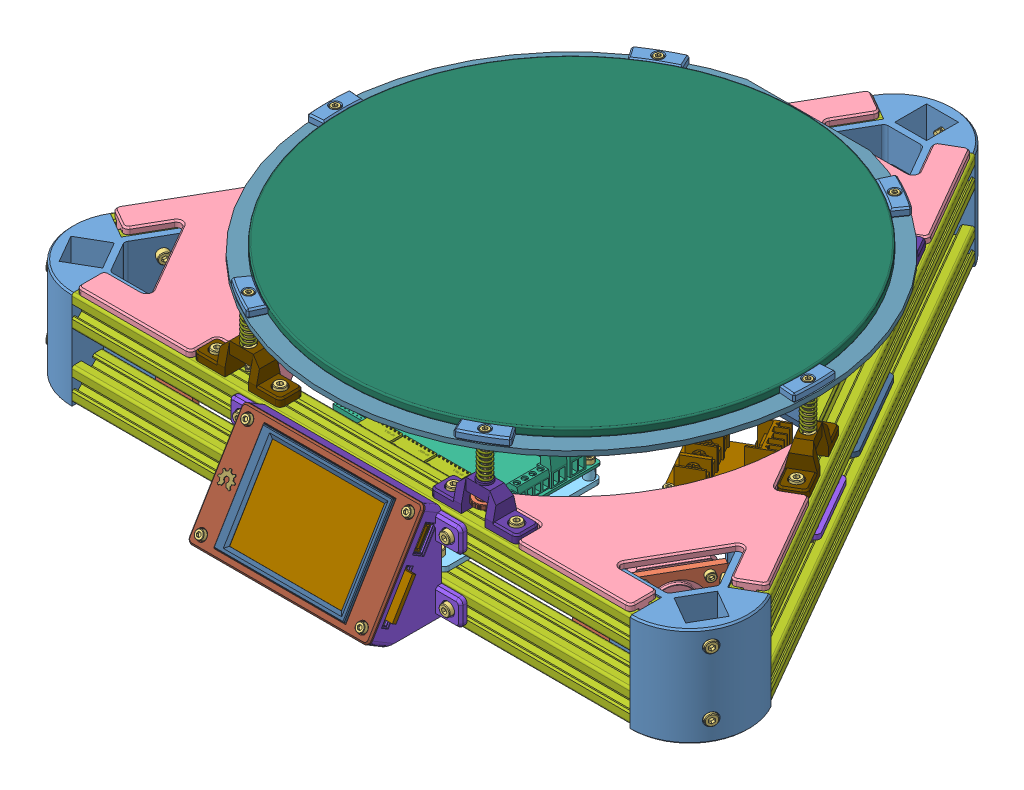
SolidWorks assembly Base Assembly, configuration Default. Lengths in mm.
Overall size (443.23 111.95 443.3).
179 component instances, 29 part files, 111 mates.
Components (placement in the parent):
- Drive Assembly-1: Drive Assembly [Default] at origin size (114.53 65.1 95.5)
  - Bottom Corner Support-1: Bottom Corner Support [Default] at origin size (78.83 63 82.18)
  - Stepper Mount-1: Stepper Mount [Default] at (0 0 0) x (1 0 0) z (0 0 1) size (55.32 60 75.5)
  - socket head cap screw_am-1: socket head cap screw_am [B18.3.1M - 3 x 0.5 x 20 Hex SHCS -- 20SHX] at (53.2197 60 -64.6791) x (0 -1 0) z (-0.546944 0 0.837169) size (23 5.5 5.5)
  - socket head cap screw_am-2: socket head cap screw_am [B18.3.1M - 3 x 0.5 x 20 Hex SHCS -- 20SHX] at (53.2197 0 -64.6791) x (0 1 0) z (-0.546944 0 0.837169) size (23 5.5 5.5)
  - socket head cap screw_am-3: socket head cap screw_am [B18.3.1M - 3 x 0.5 x 20 Hex SHCS -- 20SHX] at (82.6236 60 -13.75) x (0 -1 0) z (-0.546944 0 0.837169) size (23 5.5 5.5)
  - socket head cap screw_am-4: socket head cap screw_am [B18.3.1M - 3 x 0.5 x 20 Hex SHCS -- 20SHX] at (82.6236 0 -13.75) x (0 1 0) z (-0.546944 0 0.837169) size (23 5.5 5.5)
  - socket head cap screw_am-5: socket head cap screw_am [B18.3.1M - 4 x 0.7 x 8 Hex SHCS -- 8SHX] at (63.9931 10 -74.8395) x (-0.866026 0 -0.5) z (0.09665 0.98114 -0.167402) size (12 7 7)
  - socket head cap screw_am-6: socket head cap screw_am [B18.3.1M - 4 x 0.7 x 8 Hex SHCS -- 8SHX] at (48.7135 50 -48.3742) x (-0.866025 0 -0.5) z (-0.190925 0.924225 0.330691) size (12 7 7)
  - socket head cap screw_am-7: socket head cap screw_am [B18.3.1M - 4 x 0.7 x 8 Hex SHCS -- 8SHX] at (48.7135 10 -48.3742) x (-0.866025 0 -0.5) z (-0.190925 0.924225 0.330691) size (12 7 7)
  - socket head cap screw_am-8: socket head cap screw_am [B18.3.1M - 4 x 0.7 x 8 Hex SHCS -- 8SHX] at (66.25 10 -18) x (0 0 1) z (-1 0 0) size (12 7 7)
  - socket head cap screw_am-9: socket head cap screw_am [B18.3.1M - 4 x 0.7 x 8 Hex SHCS -- 8SHX] at (63.9931 50 -74.8395) x (-0.866026 0 -0.5) z (-0.190925 0.924225 0.330691) size (12 7 7)
  - socket head cap screw_am-10: socket head cap screw_am [B18.3.1M - 4 x 0.7 x 8 Hex SHCS -- 8SHX] at (66.25 50 -18) x (0 0 1) z (-1 0 0) size (12 7 7)
  - socket head cap screw_am-11: socket head cap screw_am [B18.3.1M - 4 x 0.7 x 8 Hex SHCS -- 8SHX] at (96.8094 10 -18.0001) x (0 0 1) z (-1 0 0) size (12 7 7)
  - socket head cap screw_am-12: socket head cap screw_am [B18.3.1M - 4 x 0.7 x 8 Hex SHCS -- 8SHX] at (96.8094 50 -18.0001) x (0 0 1) z (-1 0 0) size (12 7 7)
  - socket head cap screw_am-13: socket head cap screw_am [B18.3.1M - 4 x 0.7 x 8 Hex SHCS -- 8SHX] at (14.3627 50 -8.2923) x (0.866025 0 -0.5) z (-0.499976 0.009715 -0.865985) size (12 7 7)
  - socket head cap screw_am-14: socket head cap screw_am [B18.3.1M - 4 x 0.7 x 8 Hex SHCS -- 8SHX] at (14.3627 10 -8.2923) x (0.866025 0 -0.5) z (0.5 0 0.866025) size (12 7 7)
  - socket head cap screw_am-15: socket head cap screw_am [B18.3.1M - 3 x 0.5 x 8 Hex SHCS -- 8SHX] at (57.357 45.5 -51.013) x (0.866025 0 -0.5) z (0.5 0 0.866025) size (11 5.5 5.5)
  - socket head cap screw_am-16: socket head cap screw_am [B18.3.1M - 3 x 0.5 x 8 Hex SHCS -- 8SHX] at (72.857 45.5 -24.1662) x (0.866025 0 -0.5) z (0.5 0 0.866025) size (11 5.5 5.5)
  - socket head cap screw_am-17: socket head cap screw_am [B18.3.1M - 3 x 0.5 x 8 Hex SHCS -- 8SHX] at (57.357 14.5 -51.013) x (0.866025 0 -0.5) z (0.5 0 0.866025) size (11 5.5 5.5)
  - socket head cap screw_am-18: socket head cap screw_am [B18.3.1M - 3 x 0.5 x 8 Hex SHCS -- 8SHX] at (72.857 14.5 -24.1662) x (0.866025 0 -0.5) z (0.5 0 0.866025) size (11 5.5 5.5)
  - Drive Stepper-1: Drive Stepper [Défaut] at (69.4371 30 -40.0896) x (-0.5 0 -0.866025) z (0.866025 0 -0.5) size (45.3 42.3 72)
  - Drive Pulley-1: Drive Pulley [Конфигурация1] at (64.241 30 -37.0896) x (-0.866025 0 0.5) z (-0.435421 -0.491563 -0.754171) size (16 16 16)
  - Rubber Foot-1: Rubber Foot [Default] at (28.7942 -2.5 -16.6244) x (1 0 0) z (0 0 -1) size (15.2 2.6 15.2)
- Horizontal Extrusion-1: Horizontal Extrusion [Default] at (48 10 0) x (0 0 -1) z (1 0 0) size (20 20 354)
- Horizontal Extrusion-2: Horizontal Extrusion [Default] at (48 50 0) x (0 0 -1) z (1 0 0) size (20 20 354)
- Horizontal Extrusion-3: Horizontal Extrusion [Default] at (24 50 -41.5692) x (-0.866025 0 -0.5) z (0.5 0 -0.866025) size (20 20 354)
- Horizontal Extrusion-4: Horizontal Extrusion [Default] at (24 10 -41.5692) x (-0.866025 0 -0.5) z (0.5 0 -0.866025) size (20 20 354)
- Drive Assembly-2: Drive Assembly [Default] at (450 0 0) x (-0.5 0 -0.866025) z (0.866025 0 -0.5) size (114.53 65.1 95.5)
  - Bottom Corner Support-1: Bottom Corner Support [Default] at origin size (78.83 63 82.18)
  - Stepper Mount-1: Stepper Mount [Default] at (0 0 0) x (1 0 0) z (0 0 1) size (55.32 60 75.5)
  - socket head cap screw_am-1: socket head cap screw_am [B18.3.1M - 3 x 0.5 x 20 Hex SHCS -- 20SHX] at (53.2197 60 -64.6791) x (0 -1 0) z (-0.546944 0 0.837169) size (23 5.5 5.5)
  - socket head cap screw_am-2: socket head cap screw_am [B18.3.1M - 3 x 0.5 x 20 Hex SHCS -- 20SHX] at (53.2197 0 -64.6791) x (0 1 0) z (-0.546944 0 0.837169) size (23 5.5 5.5)
  - socket head cap screw_am-3: socket head cap screw_am [B18.3.1M - 3 x 0.5 x 20 Hex SHCS -- 20SHX] at (82.6236 60 -13.75) x (0 -1 0) z (-0.546944 0 0.837169) size (23 5.5 5.5)
  - socket head cap screw_am-4: socket head cap screw_am [B18.3.1M - 3 x 0.5 x 20 Hex SHCS -- 20SHX] at (82.6236 0 -13.75) x (0 1 0) z (-0.546944 0 0.837169) size (23 5.5 5.5)
  - socket head cap screw_am-5: socket head cap screw_am [B18.3.1M - 4 x 0.7 x 8 Hex SHCS -- 8SHX] at (63.9931 10 -74.8395) x (-0.866026 0 -0.5) z (0.09665 0.98114 -0.167402) size (12 7 7)
  - socket head cap screw_am-6: socket head cap screw_am [B18.3.1M - 4 x 0.7 x 8 Hex SHCS -- 8SHX] at (48.7135 50 -48.3742) x (-0.866025 0 -0.5) z (-0.190925 0.924225 0.330691) size (12 7 7)
  - socket head cap screw_am-7: socket head cap screw_am [B18.3.1M - 4 x 0.7 x 8 Hex SHCS -- 8SHX] at (48.7135 10 -48.3742) x (-0.866025 0 -0.5) z (-0.190925 0.924225 0.330691) size (12 7 7)
  - socket head cap screw_am-8: socket head cap screw_am [B18.3.1M - 4 x 0.7 x 8 Hex SHCS -- 8SHX] at (66.25 10 -18) x (0 0 1) z (-1 0 0) size (12 7 7)
  - socket head cap screw_am-9: socket head cap screw_am [B18.3.1M - 4 x 0.7 x 8 Hex SHCS -- 8SHX] at (63.9931 50 -74.8395) x (-0.866026 0 -0.5) z (-0.190925 0.924225 0.330691) size (12 7 7)
  - socket head cap screw_am-10: socket head cap screw_am [B18.3.1M - 4 x 0.7 x 8 Hex SHCS -- 8SHX] at (66.25 50 -18) x (0 0 1) z (-1 0 0) size (12 7 7)
  - socket head cap screw_am-11: socket head cap screw_am [B18.3.1M - 4 x 0.7 x 8 Hex SHCS -- 8SHX] at (96.8094 10 -18.0001) x (0 0 1) z (-1 0 0) size (12 7 7)
  - socket head cap screw_am-12: socket head cap screw_am [B18.3.1M - 4 x 0.7 x 8 Hex SHCS -- 8SHX] at (96.8094 50 -18.0001) x (0 0 1) z (-1 0 0) size (12 7 7)
  - socket head cap screw_am-13: socket head cap screw_am [B18.3.1M - 4 x 0.7 x 8 Hex SHCS -- 8SHX] at (14.3627 50 -8.2923) x (0.866025 0 -0.5) z (-0.499976 0.009715 -0.865985) size (12 7 7)
  - socket head cap screw_am-14: socket head cap screw_am [B18.3.1M - 4 x 0.7 x 8 Hex SHCS -- 8SHX] at (14.3627 10 -8.2923) x (0.866025 0 -0.5) z (0.5 0 0.866025) size (12 7 7)
  - socket head cap screw_am-15: socket head cap screw_am [B18.3.1M - 3 x 0.5 x 8 Hex SHCS -- 8SHX] at (57.357 45.5 -51.013) x (0.866025 0 -0.5) z (0.5 0 0.866025) size (11 5.5 5.5)
  - socket head cap screw_am-16: socket head cap screw_am [B18.3.1M - 3 x 0.5 x 8 Hex SHCS -- 8SHX] at (72.857 45.5 -24.1662) x (0.866025 0 -0.5) z (0.5 0 0.866025) size (11 5.5 5.5)
  - socket head cap screw_am-17: socket head cap screw_am [B18.3.1M - 3 x 0.5 x 8 Hex SHCS -- 8SHX] at (57.357 14.5 -51.013) x (0.866025 0 -0.5) z (0.5 0 0.866025) size (11 5.5 5.5)
  - socket head cap screw_am-18: socket head cap screw_am [B18.3.1M - 3 x 0.5 x 8 Hex SHCS -- 8SHX] at (72.857 14.5 -24.1662) x (0.866025 0 -0.5) z (0.5 0 0.866025) size (11 5.5 5.5)
  - Drive Stepper-1: Drive Stepper [Défaut] at (69.4371 30 -40.0896) x (-0.5 0 -0.866025) z (0.866025 0 -0.5) size (45.3 42.3 72)
  - Drive Pulley-1: Drive Pulley [Конфигурация1] at (64.241 30 -37.0896) x (-0.866025 0 0.5) z (-0.435421 -0.491563 -0.754171) size (16 16 16)
  - Rubber Foot-1: Rubber Foot [Default] at (28.7942 -2.5 -16.6244) x (1 0 0) z (0 0 -1) size (15.2 2.6 15.2)
- Drive Assembly-3: Drive Assembly [Default] at (225 0 -389.7114) x (-0.5 0 0.866025) z (-0.866025 0 -0.5) size (114.53 65.1 95.5)
  - Bottom Corner Support-1: Bottom Corner Support [Default] at origin size (78.83 63 82.18)
  - Stepper Mount-1: Stepper Mount [Default] at (0 0 0) x (1 0 0) z (0 0 1) size (55.32 60 75.5)
  - socket head cap screw_am-1: socket head cap screw_am [B18.3.1M - 3 x 0.5 x 20 Hex SHCS -- 20SHX] at (53.2197 60 -64.6791) x (0 -1 0) z (-0.546944 0 0.837169) size (23 5.5 5.5)
  - socket head cap screw_am-2: socket head cap screw_am [B18.3.1M - 3 x 0.5 x 20 Hex SHCS -- 20SHX] at (53.2197 0 -64.6791) x (0 1 0) z (-0.546944 0 0.837169) size (23 5.5 5.5)
  - socket head cap screw_am-3: socket head cap screw_am [B18.3.1M - 3 x 0.5 x 20 Hex SHCS -- 20SHX] at (82.6236 60 -13.75) x (0 -1 0) z (-0.546944 0 0.837169) size (23 5.5 5.5)
  - socket head cap screw_am-4: socket head cap screw_am [B18.3.1M - 3 x 0.5 x 20 Hex SHCS -- 20SHX] at (82.6236 0 -13.75) x (0 1 0) z (-0.546944 0 0.837169) size (23 5.5 5.5)
  - socket head cap screw_am-5: socket head cap screw_am [B18.3.1M - 4 x 0.7 x 8 Hex SHCS -- 8SHX] at (63.9931 10 -74.8395) x (-0.866026 0 -0.5) z (0.09665 0.98114 -0.167402) size (12 7 7)
  - socket head cap screw_am-6: socket head cap screw_am [B18.3.1M - 4 x 0.7 x 8 Hex SHCS -- 8SHX] at (48.7135 50 -48.3742) x (-0.866025 0 -0.5) z (-0.190925 0.924225 0.330691) size (12 7 7)
  - socket head cap screw_am-7: socket head cap screw_am [B18.3.1M - 4 x 0.7 x 8 Hex SHCS -- 8SHX] at (48.7135 10 -48.3742) x (-0.866025 0 -0.5) z (-0.190925 0.924225 0.330691) size (12 7 7)
  - socket head cap screw_am-8: socket head cap screw_am [B18.3.1M - 4 x 0.7 x 8 Hex SHCS -- 8SHX] at (66.25 10 -18) x (0 0 1) z (-1 0 0) size (12 7 7)
  - socket head cap screw_am-9: socket head cap screw_am [B18.3.1M - 4 x 0.7 x 8 Hex SHCS -- 8SHX] at (63.9931 50 -74.8395) x (-0.866026 0 -0.5) z (-0.190925 0.924225 0.330691) size (12 7 7)
  - socket head cap screw_am-10: socket head cap screw_am [B18.3.1M - 4 x 0.7 x 8 Hex SHCS -- 8SHX] at (66.25 50 -18) x (0 0 1) z (-1 0 0) size (12 7 7)
  - socket head cap screw_am-11: socket head cap screw_am [B18.3.1M - 4 x 0.7 x 8 Hex SHCS -- 8SHX] at (96.8094 10 -18.0001) x (0 0 1) z (-1 0 0) size (12 7 7)
  - socket head cap screw_am-12: socket head cap screw_am [B18.3.1M - 4 x 0.7 x 8 Hex SHCS -- 8SHX] at (96.8094 50 -18.0001) x (0 0 1) z (-1 0 0) size (12 7 7)
  - socket head cap screw_am-13: socket head cap screw_am [B18.3.1M - 4 x 0.7 x 8 Hex SHCS -- 8SHX] at (14.3627 50 -8.2923) x (0.866025 0 -0.5) z (-0.499976 0.009715 -0.865985) size (12 7 7)
  - socket head cap screw_am-14: socket head cap screw_am [B18.3.1M - 4 x 0.7 x 8 Hex SHCS -- 8SHX] at (14.3627 10 -8.2923) x (0.866025 0 -0.5) z (0.5 0 0.866025) size (12 7 7)
  - socket head cap screw_am-15: socket head cap screw_am [B18.3.1M - 3 x 0.5 x 8 Hex SHCS -- 8SHX] at (57.357 45.5 -51.013) x (0.866025 0 -0.5) z (0.5 0 0.866025) size (11 5.5 5.5)
  - socket head cap screw_am-16: socket head cap screw_am [B18.3.1M - 3 x 0.5 x 8 Hex SHCS -- 8SHX] at (72.857 45.5 -24.1662) x (0.866025 0 -0.5) z (0.5 0 0.866025) size (11 5.5 5.5)
  - socket head cap screw_am-17: socket head cap screw_am [B18.3.1M - 3 x 0.5 x 8 Hex SHCS -- 8SHX] at (57.357 14.5 -51.013) x (0.866025 0 -0.5) z (0.5 0 0.866025) size (11 5.5 5.5)
  - socket head cap screw_am-18: socket head cap screw_am [B18.3.1M - 3 x 0.5 x 8 Hex SHCS -- 8SHX] at (72.857 14.5 -24.1662) x (0.866025 0 -0.5) z (0.5 0 0.866025) size (11 5.5 5.5)
  - Drive Stepper-1: Drive Stepper [Défaut] at (69.4371 30 -40.0896) x (-0.5 0 -0.866025) z (0.866025 0 -0.5) size (45.3 42.3 72)
  - Drive Pulley-1: Drive Pulley [Конфигурация1] at (64.241 30 -37.0896) x (-0.866025 0 0.5) z (-0.435421 -0.491563 -0.754171) size (16 16 16)
  - Rubber Foot-1: Rubber Foot [Default] at (28.7942 -2.5 -16.6244) x (1 0 0) z (0 0 -1) size (15.2 2.6 15.2)
- Horizontal Extrusion-5: Horizontal Extrusion [Default] at (249 50 -348.1422) x (0.866025 0 -0.5) z (0.5 0 0.866025) size (20 20 354)
- Horizontal Extrusion-6: Horizontal Extrusion [Default] at (249 10 -348.1422) x (0.866025 0 -0.5) z (0.5 0 0.866025) size (20 20 354)
- Touchscreen Assembly-1: Touchscreen Assembly [Default] at (167.5 0 10) size (147 66.7 53)
  - Touchscreen Housing-1: Touchscreen Housing [Default] at origin size (147 65.67 45.48)
  - Touchscreen-1: Touchscreen [Default] at (57.5 33.7343 24.242) x (1 0 0) z (0 -0.857143 0.515079) size (116.5 15.5 65)
  - Touchscreen Bezel-1: Touchscreen Bezel [Default] at (15.2 8.5802 43.7328) x (1 0 0) z (0 -0.857143 0.515079) size (84.6 3.5 63.2)
  - Touchscreen Face-1: Touchscreen Face [Default] at (0 5.6659 45.4841) x (1 0 0) z (0 -0.857143 0.515079) size (115 2 70)
  - Logo-1: Logo [Default] at (8.2907 22.4701 36.786) x (-1 0 0) z (0 0.857143 -0.515079) size (10.55 1.3 9.36)
  - socket head cap screw_am-1: socket head cap screw_am [B18.3.1M - 3 x 0.5 x 8 Hex SHCS -- 8SHX] at (6.5 62.1548 16.2052) x (0 -0.515079 -0.857143) z (0.869565 -0.423273 0.254355) size (11 5.5 5.5)
  - socket head cap screw_am-2: socket head cap screw_am [B18.3.1M - 3 x 0.5 x 8 Hex SHCS -- 8SHX] at (108.5 62.1548 16.2052) x (0 -0.515079 -0.857143) z (0.869565 -0.423273 0.254355) size (11 5.5 5.5)
  - socket head cap screw_am-3: socket head cap screw_am [B18.3.1M - 3 x 0.5 x 8 Hex SHCS -- 8SHX] at (6.5 13.2976 45.5646) x (0 -0.515079 -0.857143) z (0.869565 -0.423273 0.254355) size (11 5.5 5.5)
  - socket head cap screw_am-4: socket head cap screw_am [B18.3.1M - 3 x 0.5 x 8 Hex SHCS -- 8SHX] at (108.5 13.2976 45.5646) x (0 -0.515079 -0.857143) z (0.869565 -0.423273 0.254355) size (11 5.5 5.5)
  - hex nut style 1_am-1: hex nut style 1_am [B18.2.4.1M - Hex nut, Style 1,  M3 x 0.5 --D-S] at (108.5 9.3057 38.9218) x (-1 0 0) z (0 0.515079 0.857143) size (5.5 6.35 2.4)
  - hex nut style 1_am-2: hex nut style 1_am [B18.2.4.1M - Hex nut, Style 1,  M3 x 0.5 --D-S] at (108.5 56.9267 7.5052) x (1 0 0) z (0 -0.515079 -0.857143) size (5.5 6.35 2.4)
  - hex nut style 1_am-3: hex nut style 1_am [B18.2.4.1M - Hex nut, Style 1,  M3 x 0.5 --D-S] at (6.5 8.0696 36.8646) x (1 0 0) z (0 -0.515079 -0.857143) size (5.5 6.35 2.4)
  - hex nut style 1_am-4: hex nut style 1_am [B18.2.4.1M - Hex nut, Style 1,  M3 x 0.5 --D-S] at (6.5 56.9267 7.5052) x (1 0 0) z (0 -0.515079 -0.857143) size (5.5 6.35 2.4)
  - socket head cap screw_am-6: socket head cap screw_am [B18.3.1M - 4 x 0.7 x 8 Hex SHCS -- 8SHX] at (-8 50 6.5) x (0 0 -1) z (0.869565 -0.493818 0) size (12 7 7)
  - socket head cap screw_am-7: socket head cap screw_am [B18.3.1M - 4 x 0.7 x 8 Hex SHCS -- 8SHX] at (-8 10 6.5) x (0 0 -1) z (0.923728 0.383049 0) size (12 7 7)
  - socket head cap screw_am-8: socket head cap screw_am [B18.3.1M - 4 x 0.7 x 8 Hex SHCS -- 8SHX] at (123 50 6.5) x (0 0 -1) z (0.923728 0.383049 0) size (12 7 7)
  - socket head cap screw_am-9: socket head cap screw_am [B18.3.1M - 4 x 0.7 x 8 Hex SHCS -- 8SHX] at (123 10 6.5) x (0 0 -1) z (0.923728 0.383049 0) size (12 7 7)
- Bed Assembly-1: Bed Assembly [Default] at (225 98.5 -129.9038) size (340.49 52.35 312.47)
  - Heat Bed-1: Heat Bed [Default] at origin size (310 3.1 305.01)
  - Print Surface-1: Print Surface [Default] at (0 3.1 0) size (290 5.25 290)
  - Bed Leveling Spring-1: Bed Leveling Spring [Default] at (150 -20 0) size (8.52 22.05 8.3)
  - Bed Leveling Spring-2: Bed Leveling Spring [Default] at (75 -20 129.9038) size (8.52 22.05 8.3)
  - Bed Leveling Spring-3: Bed Leveling Spring [Default] at (-75 -20 129.9038) size (8.52 22.05 8.3)
  - Bed Leveling Spring-4: Bed Leveling Spring [Default] at (-150 -20 0) size (8.52 22.05 8.3)
  - Bed Leveling Spring-5: Bed Leveling Spring [Default] at (-75 -20 -129.9038) size (8.52 22.05 8.3)
  - Bed Leveling Spring-6: Bed Leveling Spring [Default] at (75 -20 -129.9038) size (8.52 22.05 8.3)
  - Bed Foot-1: Bed Foot [Default] at (47.5 -38.5 122.4038) size (55 20.3 15)
  - Bed Static Foot-2: Bed Static Foot [Default] at (-102.5 -38.5 122.4038) size (55 18.5 15)
  - Bed Foot-3: Bed Foot [Default] at (82.2548 -38.5 -102.3381) x (-0.5 0 -0.866025) z (0.866025 0 -0.5) size (55 20.3 15)
  - Bed Static Foot-4: Bed Static Foot [Default] at (-95.2452 -38.5 -109.8381) x (0.5 0 -0.866025) z (0.866025 0 0.5) size (55 18.5 15)
  - Bed Foot-5: Bed Foot [Default] at (-170.2452 -38.5 20.0657) x (0.5 0 -0.866025) z (0.866025 0 0.5) size (55 20.3 15)
  - Bed Static Foot-6: Bed Static Foot [Default] at (157.2548 -38.5 27.5657) x (-0.5 0 -0.866025) z (0.866025 0 -0.5) size (55 18.5 15)
  - Print Surface Clip-1: Print Surface Clip [Default] at (0 3.1 0) x (0.866025 0 0.5) z (-0.5 0 0.866025) size (26.84 5.25 10.55)
  - Print Surface Clip-2: Print Surface Clip [Default] at (0 3.1 0) x (0.866025 0 -0.5) z (0.5 0 0.866025) size (26.84 5.25 10.55)
  - Print Surface Clip-3: Print Surface Clip [Default] at (0 3.1 0) x (0 0 -1) z (1 0 0) size (26.84 5.25 10.55)
  - Print Surface Clip-4: Print Surface Clip [Default] at (0 3.1 0) x (-0.866025 0 -0.5) z (0.5 0 -0.866025) size (26.84 5.25 10.55)
  - Print Surface Clip-5: Print Surface Clip [Default] at (0 3.1 0) x (-0.866025 0 0.5) z (-0.5 0 -0.866025) size (26.84 5.25 10.55)
  - Print Surface Clip-6: Print Surface Clip [Default] at (0 3.1 0) x (0 0 1) z (-1 0 0) size (26.84 5.25 10.55)
  - socket head cap screw_am-1: socket head cap screw_am [B18.3.1M - 3 x 0.5 x 40 Hex SHCS -- 40SHX] at (-150 8.35 0) x (0 -1 0) z (-0.546944 0 0.837169) size (43 5.5 5.5)
  - socket head cap screw_am-2: socket head cap screw_am [B18.3.1M - 3 x 0.5 x 40 Hex SHCS -- 40SHX] at (-75 8.35 129.9038) x (0 -1 0) z (-0.546944 0 0.837169) size (43 5.5 5.5)
  - socket head cap screw_am-3: socket head cap screw_am [B18.3.1M - 3 x 0.5 x 40 Hex SHCS -- 40SHX] at (75 8.35 129.9038) x (0 -1 0) z (-0.546944 0 0.837169) size (43 5.5 5.5)
  - socket head cap screw_am-4: socket head cap screw_am [B18.3.1M - 3 x 0.5 x 40 Hex SHCS -- 40SHX] at (150 8.35 0) x (0 -1 0) z (-0.546944 0 0.837169) size (43 5.5 5.5)
  - socket head cap screw_am-5: socket head cap screw_am [B18.3.1M - 3 x 0.5 x 40 Hex SHCS -- 40SHX] at (75 8.35 -129.9038) x (0 -1 0) z (-0.546944 0 0.837169) size (43 5.5 5.5)
  - socket head cap screw_am-6: socket head cap screw_am [B18.3.1M - 3 x 0.5 x 40 Hex SHCS -- 40SHX] at (-75 8.35 -129.9038) x (0 -1 0) z (-0.546944 0 0.837169) size (43 5.5 5.5)
  - Bed Leveling Knob-1: Bed Leveling Knob [Default] at (75 -32 129.9038) x (0 1 0) z (0 0 1) size (12 14 14)
  - Bed Leveling Knob-3: Bed Leveling Knob [Default] at (75 -32 -129.9038) x (0 1 0) z (0 0 1) size (12 14 14)
  - Bed Leveling Knob-5: Bed Leveling Knob [Default] at (-150 -32 0) x (0 1 0) z (0 0 1) size (12 14 14)
  - socket head cap screw_am-7: socket head cap screw_am [B18.3.1M - 4 x 0.7 x 8 Hex SHCS -- 8SHX] at (-65 -32 -147.2243) x (0 -1 0) z (0 0 1) size (12 7 7)
  - socket head cap screw_am-8: socket head cap screw_am [B18.3.1M - 4 x 0.7 x 8 Hex SHCS -- 8SHX] at (-85 -32 -112.5833) x (0 -1 0) z (-0.546944 0 0.837169) size (12 7 7)
  - socket head cap screw_am-9: socket head cap screw_am [B18.3.1M - 4 x 0.7 x 8 Hex SHCS -- 8SHX] at (-140 -32 -17.3205) x (0 -1 0) z (-0.546944 0 0.837169) size (12 7 7)
  - socket head cap screw_am-10: socket head cap screw_am [B18.3.1M - 4 x 0.7 x 8 Hex SHCS -- 8SHX] at (-160 -32 17.3205) x (0 -1 0) z (-0.546944 0 0.837169) size (12 7 7)
  - socket head cap screw_am-11: socket head cap screw_am [B18.3.1M - 4 x 0.7 x 8 Hex SHCS -- 8SHX] at (65 -32 -147.2243) x (0 -1 0) z (-0.546944 0 0.837169) size (12 7 7)
  - socket head cap screw_am-12: socket head cap screw_am [B18.3.1M - 4 x 0.7 x 8 Hex SHCS -- 8SHX] at (85 -32 -112.5833) x (0 -1 0) z (-0.546944 0 0.837169) size (12 7 7)
  - socket head cap screw_am-13: socket head cap screw_am [B18.3.1M - 4 x 0.7 x 8 Hex SHCS -- 8SHX] at (140 -32 -17.3205) x (0 -1 0) z (-0.546944 0 0.837169) size (12 7 7)
  - socket head cap screw_am-14: socket head cap screw_am [B18.3.1M - 4 x 0.7 x 8 Hex SHCS -- 8SHX] at (160 -32 17.3205) x (0 -1 0) z (-0.546944 0 0.837169) size (12 7 7)
  - socket head cap screw_am-15: socket head cap screw_am [B18.3.1M - 4 x 0.7 x 8 Hex SHCS -- 8SHX] at (95 -32 129.9038) x (0 -1 0) z (-0.546944 0 0.837169) size (12 7 7)
  - socket head cap screw_am-16: socket head cap screw_am [B18.3.1M - 4 x 0.7 x 8 Hex SHCS -- 8SHX] at (55 -32 129.9038) x (0 -1 0) z (-0.546944 0 0.837169) size (12 7 7)
  - socket head cap screw_am-17: socket head cap screw_am [B18.3.1M - 4 x 0.7 x 8 Hex SHCS -- 8SHX] at (-55 -32 129.9038) x (0 -1 0) z (-0.546944 0 0.837169) size (12 7 7)
  - socket head cap screw_am-18: socket head cap screw_am [B18.3.1M - 4 x 0.7 x 8 Hex SHCS -- 8SHX] at (-95 -32 129.9038) x (0 -1 0) z (-0.546944 0 0.837169) size (12 7 7)
  - Surface Clip End Stop-1: Surface Clip End Stop [Default] at (-75 -28.5 -129.9038) size (7.7 20.5 7.7)
  - Surface Clip End Stop-2: Surface Clip End Stop [Default] at (150 -28.5 0) size (7.7 20.5 7.7)
  - Surface Clip End Stop-3: Surface Clip End Stop [Default] at (-75 -28.5 129.9038) size (7.7 20.5 7.7)
- Corner Cover-1: Corner Cover [Default] at (1.299 60 -0.75) size (142.01 9 143.28)
- Corner Cover-2: Corner Cover [Default] at (225 60 -388.2114) x (-0.5 0 0.866025) z (-0.866025 0 -0.5) size (142.01 9 143.28)
- Corner Cover-3: Corner Cover [Default] at (448.701 60 -0.75) x (-0.5 0 -0.866025) z (0.866025 0 -0.5) size (142.01 9 143.28)
- Mainboard Bracket-1: Mainboard Bracket [Default] at (170 20 6) size (110 10 100)
- socket head cap screw_am-1: socket head cap screw_am [B18.3.1M - 4 x 0.7 x 8 Hex SHCS -- 8SHX] at (180 27 0) x (0 -1 0) z (0 0 1) size (12 7 7)
- socket head cap screw_am-2: socket head cap screw_am [B18.3.1M - 4 x 0.7 x 8 Hex SHCS -- 8SHX] at (270 27 0) x (0 -1 0) z (0 0 1) size (12 7 7)
- Mainboard Assembly-1: Mainboard Assembly [Default] at (268.9867 -16.9159 31.3576) x (-1 0 0) z (0 0 -1) size (110 19.6 84)
  - Mainboard-1: Mainboard [Default] at (43.9867 46.9159 83.3576) x (1 0 0) z (0 1 0) size (110 84 19.6)
  - Stepper Driver-1: Stepper Driver [Default] at (-9.7233 50.6059 65.5576) x (1 0 0) z (0 1 0) size (20.34 15 11)
  - Stepper Driver-2: Stepper Driver [Default] at (11.9767 50.6059 65.5576) x (1 0 0) z (0 1 0) size (20.34 15 11)
  - Stepper Driver-3: Stepper Driver [Default] at (33.6766 50.6059 65.5576) x (1 0 0) z (0 1 0) size (20.34 15 11)
  - Stepper Driver-4: Stepper Driver [Default] at (55.3766 50.6059 65.5576) x (1 0 0) z (0 1 0) size (20.34 15 11)
- socket head cap screw_am-3: socket head cap screw_am [B18.3.1M - 3 x 0.5 x 8 Hex SHCS -- 8SHX] at (174 34.6 -90) x (0 -1 0) z (0 0 1) size (11 5.5 5.5)
- socket head cap screw_am-4: socket head cap screw_am [B18.3.1M - 3 x 0.5 x 8 Hex SHCS -- 8SHX] at (276 34.6 -90) x (0 -1 0) z (0 0 1) size (11 5.5 5.5)
- socket head cap screw_am-5: socket head cap screw_am [B18.3.1M - 3 x 0.5 x 8 Hex SHCS -- 8SHX] at (276 34.6 -14) x (0 -1 0) z (0 0 1) size (11 5.5 5.5)
- socket head cap screw_am-6: socket head cap screw_am [B18.3.1M - 3 x 0.5 x 8 Hex SHCS -- 8SHX] at (174 34.6 -14) x (0 -1 0) z (0 0 1) size (11 5.5 5.5)
- Mosfet Bracket-1: Mosfet Bracket [Default] at (106.6603 20 -164.741) x (-0.5 0 0.866025) z (-0.866025 0 -0.5) size (48 10 74)
- Mosfet Bracket-2: Mosfet Bracket [Default] at (367.3397 20 -123.1718) x (-0.5 0 -0.866025) z (0.866025 0 -0.5) size (48 10 74)
- socket head cap screw_am-7: socket head cap screw_am [B18.3.1M - 4 x 0.7 x 8 Hex SHCS -- 8SHX] at (95 27 -164.5448) x (0 -1 0) z (0 0 1) size (12 7 7)
- socket head cap screw_am-8: socket head cap screw_am [B18.3.1M - 4 x 0.7 x 8 Hex SHCS -- 8SHX] at (77 27 -133.3679) x (0 -1 0) z (0 0 1) size (12 7 7)
- socket head cap screw_am-9: socket head cap screw_am [B18.3.1M - 4 x 0.7 x 8 Hex SHCS -- 8SHX] at (355 27 -164.5448) x (0 -1 0) z (0 0 1) size (12 7 7)
- socket head cap screw_am-10: socket head cap screw_am [B18.3.1M - 4 x 0.7 x 8 Hex SHCS -- 8SHX] at (373 27 -133.3679) x (0 -1 0) z (0 0 1) size (12 7 7)
- Mosfet-1: Mosfet [Default] at (119.775 30 -129.4564) x (0.5 0 -0.866025) z (0.866025 0 0.5) size (48 26.81 58)
- Mosfet-2: Mosfet [Default] at (330.225 30 -129.4564) x (0.5 0 0.866025) z (-0.866025 0 0.5) size (48 26.81 58)
- socket head cap screw_am-11: socket head cap screw_am [B18.3.1M - 3 x 0.5 x 8 Hex SHCS -- 8SHX] at (107.7583 35 -160.6429) x (0 -1 0) z (0 0 1) size (11 5.5 5.5)
- socket head cap screw_am-12: socket head cap screw_am [B18.3.1M - 3 x 0.5 x 8 Hex SHCS -- 8SHX] at (86.7583 35 -124.2698) x (0 -1 0) z (-0.546944 0 0.837169) size (11 5.5 5.5)
- socket head cap screw_am-13: socket head cap screw_am [B18.3.1M - 3 x 0.5 x 8 Hex SHCS -- 8SHX] at (152.7917 35 -134.6429) x (0 -1 0) z (-0.546944 0 0.837169) size (11 5.5 5.5)
- socket head cap screw_am-14: socket head cap screw_am [B18.3.1M - 3 x 0.5 x 8 Hex SHCS -- 8SHX] at (131.7917 35 -98.2698) x (0 -1 0) z (-0.546944 0 0.837169) size (11 5.5 5.5)
- socket head cap screw_am-15: socket head cap screw_am [B18.3.1M - 3 x 0.5 x 8 Hex SHCS -- 8SHX] at (342.2417 35 -160.6429) x (0 -1 0) z (-0.546944 0 0.837169) size (11 5.5 5.5)
- socket head cap screw_am-16: socket head cap screw_am [B18.3.1M - 3 x 0.5 x 8 Hex SHCS -- 8SHX] at (297.2083 35 -134.6429) x (0 -1 0) z (-0.546944 0 0.837169) size (11 5.5 5.5)
- socket head cap screw_am-17: socket head cap screw_am [B18.3.1M - 3 x 0.5 x 8 Hex SHCS -- 8SHX] at (363.2417 35 -124.2698) x (0 -1 0) z (-0.546944 0 0.837169) size (11 5.5 5.5)
- socket head cap screw_am-18: socket head cap screw_am [B18.3.1M - 3 x 0.5 x 8 Hex SHCS -- 8SHX] at (318.2083 35 -98.2698) x (0 -1 0) z (-0.546944 0 0.837169) size (11 5.5 5.5)
- Raspberry Pi Bracket-1: Raspberry Pi Bracket [Default] at (225 20 -389.7114) x (-0.5 0 0.866025) z (-0.866025 0 -0.5) size (153.7 10 211.82)
- socket head cap screw_am-19: socket head cap screw_am [B18.3.1M - 4 x 0.7 x 8 Hex SHCS -- 8SHX] at (137.2321 27 -237.6929) x (0 -1 0) z (-0.546944 0 0.837169) size (12 7 7)
- socket head cap screw_am-20: socket head cap screw_am [B18.3.1M - 4 x 0.7 x 8 Hex SHCS -- 8SHX] at (110.9004 27 -192.0852) x (0 -1 0) z (-0.546944 0 0.837169) size (12 7 7)
- socket head cap screw_am-21: socket head cap screw_am [B18.3.1M - 4 x 0.7 x 8 Hex SHCS -- 8SHX] at (312.7679 27 -237.6929) x (0 -1 0) z (-0.546944 0 0.837169) size (12 7 7)
- socket head cap screw_am-22: socket head cap screw_am [B18.3.1M - 4 x 0.7 x 8 Hex SHCS -- 8SHX] at (339.0996 27 -192.0852) x (0 -1 0) z (-0.546944 0 0.837169) size (12 7 7)
- Raspberry Pi-1: Raspberry Pi [Default] at (219.058 30.33 -217.2998) x (-1 0 0) z (0 1 0) size (89.64 57.31 18.59)
Mates (geometry in assembly coordinates):
- Coincident1: coincident: plane of Drive Assembly-1/Bottom Corner Support-1 through (48 60 -10) normal (0 0 1); plane of Horizontal Extrusion-1 through (402 1.5 -10) normal (0 0 -1)
- Coincident2: coincident: plane of Drive Assembly-1/Bottom Corner Support-1 through (48 0 -27.7128) normal (0 -1 0); plane of Horizontal Extrusion-1 through (402 0 -4.1) normal (0 -1 0)
- Coincident3: coincident: plane of Drive Assembly-1/Bottom Corner Support-1 through (48 60 10) normal (1 0 0); plane of Horizontal Extrusion-1 through (48 18.5 8.5) normal (-1 0 0)
- Coincident4: coincident: plane of Drive Assembly-1/Bottom Corner Support-1 through (48 60 -10) normal (0 0 1); plane of Horizontal Extrusion-2 through (402 41.5 -10) normal (0 0 -1)
- Coincident5: coincident: plane of Drive Assembly-1/Bottom Corner Support-1 through (48 60 -27.7128) normal (0 1 0); plane of Horizontal Extrusion-2 through (402 60 -4.1) normal (0 1 0)
- Coincident6: coincident: plane of Drive Assembly-1/Bottom Corner Support-1 through (48 60 10) normal (1 0 0); plane of Horizontal Extrusion-2 through (48 58.5 8.5) normal (-1 0 0)
- Coincident7: coincident: plane of Drive Assembly-1/Bottom Corner Support-1 through (32.6603 60 -36.5692) normal (-0.866025 0 -0.5); plane of Horizontal Extrusion-4 through (209.6603 1.5 -343.1422) normal (0.866025 0 0.5)
- Coincident8: coincident: plane of Drive Assembly-1/Bottom Corner Support-1 through (48 0 -27.7128) normal (0 -1 0); plane of Horizontal Extrusion-4 through (204.5507 0 -346.0922) normal (0 -1 0)
- Coincident9: coincident: plane of Drive Assembly-1/Bottom Corner Support-1 through (15.3397 60 -46.5692) normal (0.5 0 -0.866025); plane of Horizontal Extrusion-4 through (31.3612 18.5 -37.3192) normal (-0.5 0 0.866025)
- Coincident10: coincident: plane of Drive Assembly-1/Bottom Corner Support-1 through (32.6603 60 -36.5692) normal (-0.866025 0 -0.5); plane of Horizontal Extrusion-3 through (209.6603 41.5 -343.1422) normal (0.866025 0 0.5)
- Coincident11: coincident: plane of Drive Assembly-1/Bottom Corner Support-1 through (48 60 -27.7128) normal (0 1 0); plane of Horizontal Extrusion-3 through (204.5507 60 -346.0922) normal (0 1 0)
- Coincident12: coincident: plane of Drive Assembly-1/Bottom Corner Support-1 through (15.3397 60 -46.5692) normal (0.5 0 -0.866025); plane of Horizontal Extrusion-3 through (31.3612 58.5 -37.3192) normal (-0.5 0 0.866025)
- Coincident13: coincident: plane of Horizontal Extrusion-1 through (402 1.5 -10) normal (0 0 -1); plane of Drive Assembly-2/Bottom Corner Support-1 through (402 60 -10) normal (0 0 1)
- Coincident14: coincident: plane of Horizontal Extrusion-1 through (402 18.5 8.5) normal (1 0 0); plane of Drive Assembly-2/Bottom Corner Support-1 through (402 60 10) normal (-1 0 0)
- Coincident15: coincident: plane of Horizontal Extrusion-1 through (402 0 -4.1) normal (0 -1 0); plane of Drive Assembly-2/Bottom Corner Support-1 through (402 0 -27.7128) normal (0 -1 0)
- Coincident16: coincident: plane of Horizontal Extrusion-4 through (209.6603 1.5 -343.1422) normal (0.866025 0 0.5); plane of Drive Assembly-3/Bottom Corner Support-1 through (209.6603 60 -343.1422) normal (-0.866025 0 -0.5)
- Coincident17: coincident: plane of Horizontal Extrusion-4 through (208.3612 18.5 -343.8922) normal (0.5 0 -0.866025); plane of Drive Assembly-3/Bottom Corner Support-1 through (192.3397 60 -353.1422) normal (-0.5 0 0.866025)
- Coincident18: coincident: plane of Horizontal Extrusion-4 through (204.5507 0 -346.0922) normal (0 -1 0); plane of Drive Assembly-3/Bottom Corner Support-1 through (225 0 -334.2858) normal (0 -1 0)
- Coincident19: coincident: plane of Drive Assembly-2/Bottom Corner Support-1 through (417.3397 60 -36.5692) normal (0.866025 0 -0.5); plane of Horizontal Extrusion-6 through (417.3397 1.5 -36.5692) normal (-0.866025 0 0.5)
- Coincident20: coincident: plane of Drive Assembly-2/Bottom Corner Support-1 through (434.6603 60 -46.5692) normal (-0.5 0 -0.866025); plane of Horizontal Extrusion-6 through (418.6388 18.5 -37.3192) normal (0.5 0 0.866025)
- Coincident21: coincident: plane of Drive Assembly-2/Bottom Corner Support-1 through (402 0 -27.7128) normal (0 -1 0); plane of Horizontal Extrusion-6 through (422.4493 0 -39.5192) normal (0 -1 0)
- Coincident22: coincident: plane of Drive Assembly-3/Bottom Corner Support-1 through (240.3397 60 -343.1422) normal (0.866025 0 -0.5); plane of Horizontal Extrusion-6 through (417.3397 1.5 -36.5692) normal (-0.866025 0 0.5)
- Coincident23: coincident: plane of Drive Assembly-3/Bottom Corner Support-1 through (257.6603 60 -353.1422) normal (0.5 0 0.866025); plane of Horizontal Extrusion-6 through (241.6388 18.5 -343.8922) normal (-0.5 0 -0.866025)
- Coincident24: coincident: plane of Drive Assembly-2/Bottom Corner Support-1 through (417.3397 60 -36.5692) normal (0.866025 0 -0.5); plane of Horizontal Extrusion-5 through (417.3397 41.5 -36.5692) normal (-0.866025 0 0.5)
- Coincident25: coincident: plane of Drive Assembly-2/Bottom Corner Support-1 through (434.6603 60 -46.5692) normal (-0.5 0 -0.866025); plane of Horizontal Extrusion-5 through (418.6388 58.5 -37.3192) normal (0.5 0 0.866025)
- Coincident26: coincident: plane of Drive Assembly-2/Bottom Corner Support-1 through (402 60 -27.7128) normal (0 1 0); plane of Horizontal Extrusion-5 through (422.4493 60 -39.5192) normal (0 1 0)
- Distance1: distance = 2 mm: plane of Touchscreen Assembly-1/Touchscreen Housing-1 through (280.5 58 10) normal (0 1 0); plane of Horizontal Extrusion-2 through (402 60 4.1) normal (0 1 0)
- Coincident28: coincident: plane of Horizontal Extrusion-2 through (402 58.5 10) normal (0 0 1); plane of Touchscreen Assembly-1/Touchscreen Housing-1 through (282.5 0 10) normal (0 0 -1)
- Distance3: distance = 119.5 mm: plane of Drive Assembly-1/Bottom Corner Support-1 through (48 60 10) normal (1 0 0); plane of Touchscreen Assembly-1/Touchscreen Housing-1 through (167.5 0 10) normal (-1 0 0)
- Parallel1: parallel: plane of Horizontal Extrusion-2 through (402 58.5 10) normal (0 0 1); plane of Bed Assembly-1/Bed Foot-1 through (272.5 60 7.5) normal (0 0 1)
- Parallel2: parallel: plane of Horizontal Extrusion-5 through (434.6603 58.5 -46.5692) normal (0.866025 0 -0.5); plane of Bed Assembly-1/Bed Foot-3 through (320.2452 60 -239.7419) normal (0.866025 0 -0.5)
- Parallel3: parallel: plane of Horizontal Extrusion-3 through (192.3397 58.5 -353.1422) normal (-0.866025 0 -0.5); plane of Bed Assembly-1/Bed Foot-5 through (54.7548 60 -109.8381) normal (-0.866025 0 -0.5)
- Coincident35: coincident: plane of Horizontal Extrusion-2 through (402 60 4.1) normal (0 1 0); plane of Bed Assembly-1/Bed Foot-1 through (307.5 60 7.5) normal (0 -1 0)
- Distance5: distance = 2.5 mm: plane of Bed Assembly-1/Bed Foot-5 through (54.7548 60 -109.8381) normal (-0.866025 0 -0.5); plane of Horizontal Extrusion-3 through (192.3397 58.5 -353.1422) normal (-0.866025 0 -0.5)
- Distance7: distance = 2.5 mm: plane of Bed Assembly-1/Bed Foot-3 through (320.2452 60 -239.7419) normal (0.866025 0 -0.5); plane of Horizontal Extrusion-5 through (434.6603 58.5 -46.5692) normal (0.866025 0 -0.5)
- Coincident36: coincident: line of Horizontal Extrusion-2 through (402 60 8.5) axis (-1 0 0); line of Corner Cover-1 through (52.299 60 8.5) axis (1 0 0)
- Coincident37: coincident: line of Horizontal Extrusion-3 through (193.6388 60 -352.3922) axis (-0.5 0 0.866025); line of Corner Cover-1 through (52.0133 60 -107.0897) axis (-0.5 0 0.866025)
- Coincident38: coincident: line of Horizontal Extrusion-5 through (433.3612 60 -45.8192) axis (-0.5 0 -0.866025); line of Corner Cover-3 through (431.2117 60 -49.5423) axis (-0.5 0 -0.866025)
- Coincident39: coincident: line of Horizontal Extrusion-2 through (402 60 8.5) axis (-1 0 0); line of Corner Cover-3 through (331.251 60 8.5) axis (1 0 0)
- Coincident40: coincident: line of Horizontal Extrusion-5 through (433.3612 60 -45.8192) axis (-0.5 0 -0.866025); line of Corner Cover-2 through (291.7357 60 -291.1217) axis (-0.5 0 -0.866025)
- Coincident41: coincident: line of Horizontal Extrusion-3 through (193.6388 60 -352.3922) axis (-0.5 0 0.866025); line of Corner Cover-2 through (191.4893 60 -348.6691) axis (-0.5 0 0.866025)
- Coincident42: coincident: plane of Horizontal Extrusion-1 through (402 20 -4.1) normal (0 1 0); plane of Mainboard Bracket-1 through (170 20 6) normal (0 -1 0)
- Distance8: distance = 16 mm: plane of Mainboard Bracket-1 through (170 23 6) normal (0 0 1); plane of Horizontal Extrusion-1 through (402 18.5 -10) normal (0 0 -1)
- Distance10: distance = 2.5 mm: plane of Touchscreen Assembly-1/Touchscreen Housing-1 through (282.5 0 10) normal (1 0 0); plane of Mainboard Bracket-1 through (280 23 -94) normal (1 0 0)
- Concentric1: concentric: cylinder of Mainboard Bracket-1 through (270 30 0) axis (0 -1 0) radius 2.125; cylinder of socket head cap screw_am-2 through (270 58.75 0) axis (0 1 0) radius 3.5
- Coincident48: coincident: plane of Mainboard Bracket-1 through (170 23 6) normal (0 1 0); plane of socket head cap screw_am-2 through (273.5 23 0) normal (0 -1 0)
- Concentric2: concentric: cylinder of Mainboard Bracket-1 through (180 30 0) axis (0 -1 0) radius 2.125; cylinder of socket head cap screw_am-1 through (180 58.75 0) axis (0 1 0) radius 3.5
- Coincident49: coincident: plane of Mainboard Bracket-1 through (170 23 6) normal (0 1 0); plane of socket head cap screw_am-1 through (183.5 23 0) normal (0 -1 0)
- Coincident50: coincident: plane of Mainboard Bracket-1 through (276 30 -14) normal (0 1 0); plane of Mainboard Assembly-1/Mainboard-1 through (225 30 -52) normal (0 -1 0)
- Concentric5: concentric: cylinder of Mainboard Bracket-1 through (276 23 -14) axis (0 -1 0) radius 1.25; cylinder of Mainboard Assembly-1/Mainboard-1 through (276 31.6 -14) axis (0 -1 0) radius 1.5
- Concentric6: concentric: cylinder of Mainboard Bracket-1 through (174 23 -90) axis (0 -1 0) radius 1.25; cylinder of Mainboard Assembly-1/Mainboard-1 through (174 31.6 -90) axis (0 -1 0) radius 1.5
- Concentric7: concentric: cylinder of Mainboard Assembly-1/Mainboard-1 through (174 31.6 -90) axis (0 -1 0) radius 1.5; cylinder of socket head cap screw_am-3 through (174 66.35 -90) axis (0 1 0) radius 2.75
- Coincident51: coincident: plane of Mainboard Assembly-1/Mainboard-1 through (225 31.6 -52) normal (0 1 0); plane of socket head cap screw_am-3 through (176.75 31.6 -90) normal (0 -1 0)
- Concentric8: concentric: cylinder of Mainboard Assembly-1/Mainboard-1 through (276 31.6 -90) axis (0 -1 0) radius 1.5; cylinder of socket head cap screw_am-4 through (276 66.35 -90) axis (0 1 0) radius 2.75
- Coincident52: coincident: plane of Mainboard Assembly-1/Mainboard-1 through (225 31.6 -52) normal (0 1 0); plane of socket head cap screw_am-4 through (278.75 31.6 -90) normal (0 -1 0)
- Concentric9: concentric: cylinder of Mainboard Assembly-1/Mainboard-1 through (174 31.6 -14) axis (0 -1 0) radius 1.5; cylinder of socket head cap screw_am-6 through (174 66.35 -14) axis (0 1 0) radius 2.75
- Coincident53: coincident: plane of Mainboard Assembly-1/Mainboard-1 through (225 31.6 -52) normal (0 1 0); plane of socket head cap screw_am-6 through (176.75 31.6 -14) normal (0 -1 0)
- Concentric10: concentric: cylinder of Mainboard Assembly-1/Mainboard-1 through (276 31.6 -14) axis (0 -1 0) radius 1.5; cylinder of socket head cap screw_am-5 through (276 66.35 -14) axis (0 1 0) radius 2.75
- Coincident54: coincident: plane of Mainboard Assembly-1/Mainboard-1 through (225 31.6 -52) normal (0 1 0); plane of socket head cap screw_am-5 through (278.75 31.6 -14) normal (0 -1 0)
- Coincident55: coincident: plane of Horizontal Extrusion-4 through (204.5507 20 -346.0922) normal (0 1 0); plane of Mosfet Bracket-1 through (106.6603 20 -164.741) normal (0 -1 0)
- Distance11: distance = 16 mm: plane of Mosfet Bracket-1 through (92.8038 23 -172.741) normal (-0.866025 0 -0.5); plane of Horizontal Extrusion-4 through (209.6603 18.5 -343.1422) normal (0.866025 0 0.5)
- Distance13: distance = 100 mm: plane of Mosfet Bracket-1 through (132.8897 23 -94.1718) normal (-0.5 0 0.866025); plane of Drive Assembly-1/Bottom Corner Support-1 through (15.3397 60 -46.5692) normal (0.5 0 -0.866025)
- Coincident59: coincident: plane of Horizontal Extrusion-6 through (422.4493 20 -39.5192) normal (0 1 0); plane of Mosfet Bracket-2 through (367.3397 20 -123.1718) normal (0 -1 0)
- Distance14: distance = 16 mm: plane of Mosfet Bracket-2 through (381.1962 23 -131.1718) normal (0.866025 0 -0.5); plane of Horizontal Extrusion-6 through (417.3397 18.5 -36.5692) normal (-0.866025 0 0.5)
- Distance15: distance = 100 mm: plane of Mosfet Bracket-2 through (367.3397 23 -123.1718) normal (0.5 0 0.866025); plane of Drive Assembly-2/Bottom Corner Support-1 through (434.6603 60 -46.5692) normal (-0.5 0 -0.866025)
- Concentric11: concentric: cylinder of Mosfet Bracket-1 through (95 30 -164.5448) axis (0 -1 0) radius 2.125; cylinder of socket head cap screw_am-7 through (95 58.75 -164.5448) axis (0 1 0) radius 3.5
- Concentric12: concentric: cylinder of Mosfet Bracket-1 through (77 30 -133.3679) axis (0 -1 0) radius 2.125; cylinder of socket head cap screw_am-8 through (77 58.75 -133.3679) axis (0 1 0) radius 3.5
- Concentric13: concentric: cylinder of Mosfet Bracket-2 through (355 30 -164.5448) axis (0 -1 0) radius 2.125; cylinder of socket head cap screw_am-9 through (355 58.75 -164.5448) axis (0 1 0) radius 3.5
- Concentric14: concentric: cylinder of Mosfet Bracket-2 through (373 30 -133.3679) axis (0 -1 0) radius 2.125; cylinder of socket head cap screw_am-10 through (373 58.75 -133.3679) axis (0 1 0) radius 3.5
- Coincident62: coincident: plane of Mosfet Bracket-2 through (367.3397 23 -123.1718) normal (0 1 0); plane of socket head cap screw_am-9 through (358.5 23 -164.5448) normal (0 -1 0)
- Coincident63: coincident: plane of Mosfet Bracket-2 through (367.3397 23 -123.1718) normal (0 1 0); plane of socket head cap screw_am-10 through (376.5 23 -133.3679) normal (0 -1 0)
- Coincident64: coincident: plane of Mosfet Bracket-1 through (106.6603 23 -164.741) normal (0 1 0); plane of socket head cap screw_am-7 through (98.5 23 -164.5448) normal (0 -1 0)
- Coincident65: coincident: plane of Mosfet Bracket-1 through (106.6603 23 -164.741) normal (0 1 0); plane of socket head cap screw_am-8 through (80.5 23 -133.3679) normal (0 -1 0)
- Concentric15: concentric: cylinder of Mosfet Bracket-1 through (107.7583 23 -160.6429) axis (0 -1 0) radius 1.25; cylinder of Mosfet-1 through (107.7583 30 -160.6429) axis (0 1 0) radius 1.75
- Concentric16: concentric: cylinder of Mosfet Bracket-1 through (131.7917 23 -98.2698) axis (0 -1 0) radius 1.25; cylinder of Mosfet-1 through (131.7917 30 -98.2698) axis (0 1 0) radius 1.75
- Coincident66: coincident: plane of Mosfet Bracket-1 through (131.7917 30 -98.2698) normal (0 1 0); plane of Mosfet-1 through (119.775 30 -129.4564) normal (0 -1 0)
- Coincident67: coincident: plane of Mosfet Bracket-2 through (297.2083 30 -134.6429) normal (0 1 0); plane of Mosfet-2 through (330.225 30 -129.4564) normal (0 -1 0)
- Concentric17: concentric: cylinder of Mosfet Bracket-2 through (363.2417 23 -124.2698) axis (0 -1 0) radius 1.25; cylinder of Mosfet-2 through (363.2417 30 -124.2698) axis (0 1 0) radius 1.75
- Concentric18: concentric: cylinder of Mosfet Bracket-2 through (297.2083 23 -134.6429) axis (0 -1 0) radius 1.25; cylinder of Mosfet-2 through (297.2083 30 -134.6429) axis (0 1 0) radius 1.75
- Concentric19: concentric: cylinder of socket head cap screw_am-11 through (107.7583 66.75 -160.6429) axis (0 1 0) radius 2.75; cylinder of Mosfet-1 through (107.7583 30 -160.6429) axis (0 1 0) radius 1.75
- Concentric20: concentric: cylinder of socket head cap screw_am-12 through (86.7583 66.75 -124.2698) axis (0 1 0) radius 2.75; cylinder of Mosfet-1 through (86.7583 30 -124.2698) axis (0 1 0) radius 1.75
- Concentric22: concentric: cylinder of socket head cap screw_am-13 through (152.7917 66.75 -134.6429) axis (0 1 0) radius 2.75; cylinder of Mosfet-1 through (152.7917 30 -134.6429) axis (0 1 0) radius 1.75
- Concentric23: concentric: cylinder of socket head cap screw_am-14 through (131.7917 66.75 -98.2698) axis (0 1 0) radius 2.75; cylinder of Mosfet-1 through (131.7917 30 -98.2698) axis (0 1 0) radius 1.75
- Coincident68: coincident: plane of Mosfet-1 through (119.775 32 -129.4564) normal (0 1 0); plane of socket head cap screw_am-14 through (134.0939 32 -96.7657) normal (0 -1 0)
- Coincident69: coincident: plane of Mosfet-1 through (119.775 32 -129.4564) normal (0 1 0); plane of socket head cap screw_am-12 through (89.0605 32 -122.7657) normal (0 -1 0)
- Coincident70: coincident: plane of Mosfet-1 through (119.775 32 -129.4564) normal (0 1 0); plane of socket head cap screw_am-13 through (155.0939 32 -133.1388) normal (0 -1 0)
- Coincident71: coincident: plane of Mosfet-1 through (119.775 32 -129.4564) normal (0 1 0); plane of socket head cap screw_am-11 through (110.5083 32 -160.6429) normal (0 -1 0)
- Concentric24: concentric: cylinder of socket head cap screw_am-15 through (342.2417 66.75 -160.6429) axis (0 1 0) radius 2.75; cylinder of Mosfet-2 through (342.2417 30 -160.6429) axis (0 1 0) radius 1.75
- Concentric25: concentric: cylinder of socket head cap screw_am-16 through (297.2083 66.75 -134.6429) axis (0 1 0) radius 2.75; cylinder of Mosfet-2 through (297.2083 30 -134.6429) axis (0 1 0) radius 1.75
- Concentric26: concentric: cylinder of socket head cap screw_am-17 through (363.2417 66.75 -124.2698) axis (0 1 0) radius 2.75; cylinder of Mosfet-2 through (363.2417 30 -124.2698) axis (0 1 0) radius 1.75
- Concentric27: concentric: cylinder of socket head cap screw_am-18 through (318.2083 66.75 -98.2698) axis (0 1 0) radius 2.75; cylinder of Mosfet-2 through (318.2083 30 -98.2698) axis (0 1 0) radius 1.75
- Coincident72: coincident: plane of Mosfet-2 through (330.225 32 -129.4564) normal (0 1 0); plane of socket head cap screw_am-17 through (365.5439 32 -122.7657) normal (0 -1 0)
- Coincident73: coincident: plane of Mosfet-2 through (330.225 32 -129.4564) normal (0 1 0); plane of socket head cap screw_am-15 through (344.5439 32 -159.1388) normal (0 -1 0)
- Coincident74: coincident: plane of Mosfet-2 through (330.225 32 -129.4564) normal (0 1 0); plane of socket head cap screw_am-16 through (299.5106 32 -133.1388) normal (0 -1 0)
- Coincident75: coincident: plane of Mosfet-2 through (330.225 32 -129.4564) normal (0 1 0); plane of socket head cap screw_am-18 through (320.5106 32 -96.7657) normal (0 -1 0)
- Coincident76: coincident: plane of Horizontal Extrusion-4 through (204.5507 20 -346.0922) normal (0 1 0); plane of Raspberry Pi Bracket-1 through (225 20 -389.7114) normal (0 -1 0)
- Parallel4: parallel: plane of Horizontal Extrusion-4 through (192.3397 18.5 -353.1422) normal (-0.866025 0 -0.5); plane of Raspberry Pi Bracket-1 through (133.3038 23 -242.889) normal (-0.866025 0 -0.5)
- Parallel5: parallel: plane of Horizontal Extrusion-6 through (434.6603 18.5 -46.5692) normal (0.866025 0 -0.5); plane of Raspberry Pi Bracket-1 through (316.6962 23 -242.889) normal (0.866025 0 -0.5)
- Distance16: distance = 4 mm: plane of Raspberry Pi Bracket-1 through (133.3038 23 -242.889) normal (-0.866025 0 -0.5); plane of Horizontal Extrusion-4 through (192.3397 18.5 -353.1422) normal (-0.866025 0 -0.5)
- Distance17: distance = 4 mm: plane of Raspberry Pi Bracket-1 through (316.6962 23 -242.889) normal (0.866025 0 -0.5); plane of Horizontal Extrusion-6 through (434.6603 18.5 -46.5692) normal (0.866025 0 -0.5)
- Concentric28: concentric: cylinder of Raspberry Pi Bracket-1 through (137.2321 20 -237.6929) axis (0 1 0) radius 2.125; cylinder of socket head cap screw_am-19 through (137.2321 58.75 -237.6929) axis (0 1 0) radius 3.5
- Coincident81: coincident: plane of Raspberry Pi Bracket-1 through (225 23 -389.7114) normal (0 1 0); plane of socket head cap screw_am-19 through (140.1621 23 -235.7786) normal (0 -1 0)
- Concentric29: concentric: cylinder of Raspberry Pi Bracket-1 through (110.9004 20 -192.0852) axis (0 1 0) radius 2.125; cylinder of socket head cap screw_am-20 through (110.9004 58.75 -192.0852) axis (0 1 0) radius 3.5
- Coincident82: coincident: plane of Raspberry Pi Bracket-1 through (225 23 -389.7114) normal (0 1 0); plane of socket head cap screw_am-20 through (113.8305 23 -190.1709) normal (0 -1 0)
- Concentric30: concentric: cylinder of Raspberry Pi Bracket-1 through (312.7679 20 -237.6929) axis (0 1 0) radius 2.125; cylinder of socket head cap screw_am-21 through (312.7679 58.75 -237.6929) axis (0 1 0) radius 3.5
- Coincident83: coincident: plane of Raspberry Pi Bracket-1 through (225 23 -389.7114) normal (0 1 0); plane of socket head cap screw_am-21 through (315.698 23 -235.7786) normal (0 -1 0)
- Concentric31: concentric: cylinder of Raspberry Pi Bracket-1 through (339.0996 20 -192.0852) axis (0 1 0) radius 2.125; cylinder of socket head cap screw_am-22 through (339.0996 58.75 -192.0852) axis (0 1 0) radius 3.5
- Coincident84: coincident: plane of Raspberry Pi Bracket-1 through (225 23 -389.7114) normal (0 1 0); plane of socket head cap screw_am-22 through (342.0297 23 -190.1709) normal (0 -1 0)
- Concentric32: concentric: cylinder of Raspberry Pi Bracket-1 through (264 20 -239.389) axis (0 1 0) radius 1.25; cylinder of Raspberry Pi-1 through (264 29.58 -239.389) axis (0 1 0) radius 1.375
- Concentric33: concentric: cylinder of Raspberry Pi Bracket-1 through (206 20 -190.389) axis (0 1 0) radius 1.25; cylinder of Raspberry Pi-1 through (206 29.58 -190.389) axis (0 1 0) radius 1.375
- Coincident85: coincident: plane of Raspberry Pi Bracket-1 through (206 30 -190.389) normal (0 1 0); plane of Raspberry Pi-1 through (182.5758 30 -186.889) normal (0 -1 0)
